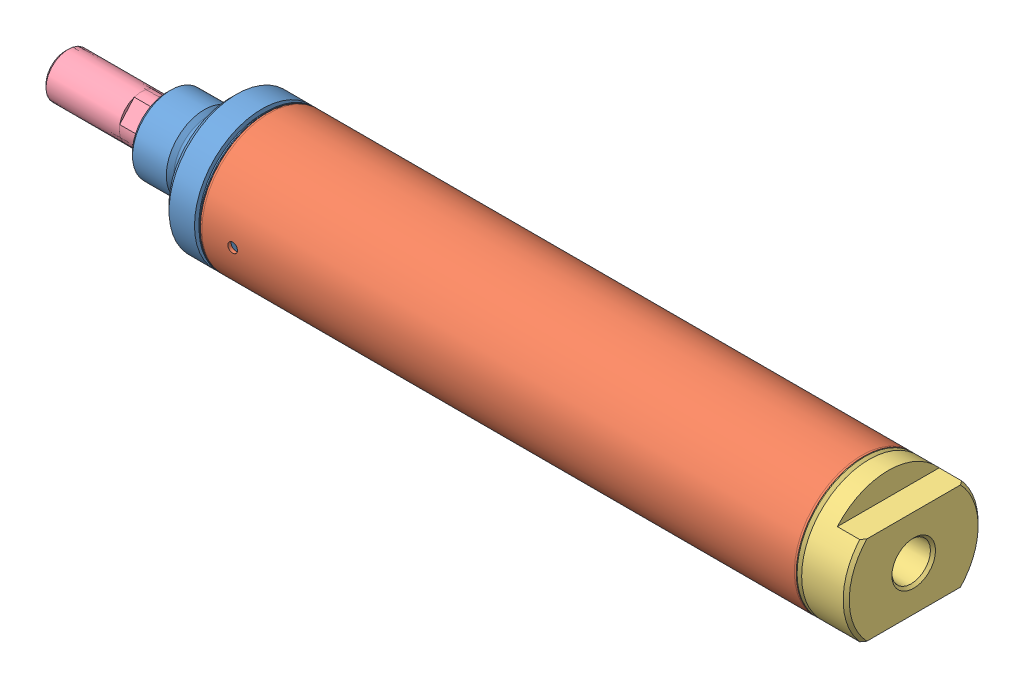
SolidWorks assembly 122_5, configuration Default. Lengths in mm.
Overall size (211.84 45.08 45.08).
5 component instances, 5 part files, 11 mates.
Components (placement in the parent):
- 122_5C0000_0_dummy-1: 122_5C0000_0_dummy [Default] at origin
- 12000-0_rod_guide-1: 12000-0_rod_guide [Default] at origin size (39.67 33.69 33.69)
- 12-5_8882C-1: 12-5_8882C [Default] at (24.7396 0 0) size (151.39 33.69 33.69)
- 120000_rear_head-1: 120000_rear_head [Default] at (168.9608 0 0) size (17.48 33.69 33.69)
- C-122_50_rod-1: C-122_50_rod [Default] x (1 0 0) z (0 0.660922 0.750455) size (194.36 31.94 31.94)
Mates (geometry in assembly coordinates):
- Distance2: distance = 0 mm aligned: plane of 12000-0_rod_guide-1 through (0 0 0) normal (1 0 0); plane of 122_5C0000_0_dummy-1 through (0 0 0) normal (1 0 0)
- Coincident1: coincident aligned: line of 122_5C0000_0_dummy-1 through (80.9 0 0) axis (-1 0 0); line of 12000-0_rod_guide-1 through (80.9 0 0) axis (-1 0 0)
- Angle3: planar angle = 0 rad aligned: plane of 12000-0_rod_guide-1 through (0 0 0) normal (0 0 -1); plane of 122_5C0000_0_dummy-1 through (0 0 0) normal (0 0 -1)
- Distance4: distance = 0 mm aligned: plane of 12-5_8882C-1 through (24.7396 0 0) normal (1 0 0); plane of 12000-0_rod_guide-1 through (24.7396 0 0) normal (1 0 0)
- Coincident2: coincident aligned: line of 12000-0_rod_guide-1 through (80.9 0 0) axis (-1 0 0); line of 12-5_8882C-1 through (105.6396 0 0) axis (-1 0 0)
- Angle6: planar angle = 0 rad aligned: plane of 12-5_8882C-1 through (24.7396 0 0) normal (0 0 -1); plane of 12000-0_rod_guide-1 through (0 0 0) normal (0 0 -1)
- Distance6: distance = 0 mm aligned: plane of 120000_rear_head-1 through (174.2948 0 0) normal (1 0 0); plane of 12-5_8882C-1 through (174.2948 0 0) normal (1 0 0)
- Coincident3: coincident aligned: line of 12-5_8882C-1 through (105.6396 0 0) axis (-1 0 0); line of 120000_rear_head-1 through (249.8608 0 0) axis (-1 0 0)
- Angle9: planar angle = 0 rad aligned: plane of 120000_rear_head-1 through (168.9608 0 0) normal (0 0 -1); plane of 12-5_8882C-1 through (24.7396 0 0) normal (0 0 -1)
- LimitDistance2: limit distance = 0 mm aligned: plane of C-122_50_rod-1; plane of 12000-0_rod_guide-1 through (0 0 0) normal (1 0 0)
- Coincident5: coincident aligned: line of 12000-0_rod_guide-1 through (80.9 0 0) axis (-1 0 0); line of C-122_50_rod-1 through (80.9 0 0) axis (-1 0 0)
